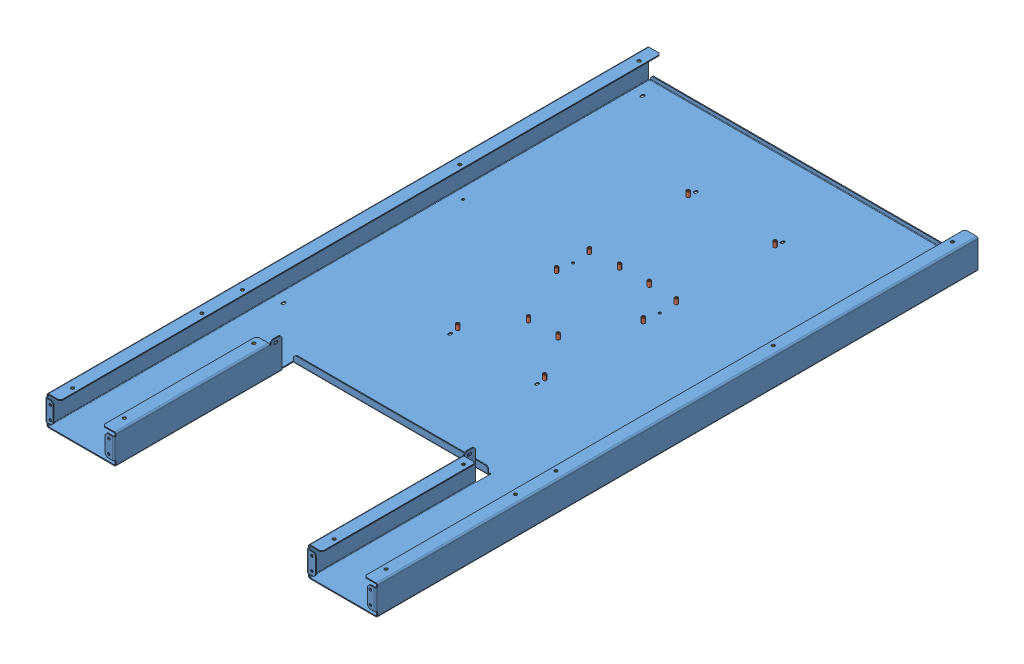
SolidWorks assembly OB_1735311-C_1U-Housing, configuration Default. Lengths in mm.
Overall size (444.51 42.17 812.8).
27 component instances, 3 part files, 11 mates.
Components (placement in the parent):
- OB_1735311-C_1U-Housing-1: OB_1735311-C_1U-Housing [Default] at origin size (444.51 42.17 812.8)
- PEM-STANDOFF_BSO-440-10ZI-5: PEM-STANDOFF_BSO-440-10ZI [93090A420] at (-58.42 3.9688 -154.94) x (0 -1 0) z (1 0 0) size (8.15 5.5 4.76)
- S-440-1ZI_SELF-CLINCHING-NUT-6: S-440-1ZI_SELF-CLINCHING-NUT [95185A120] at (-210.82 36.6268 -241.3) x (1 0 0) z (0 -1 0) size (6.35 6.35 3.2)
- S-440-1ZI_SELF-CLINCHING-NUT-8: S-440-1ZI_SELF-CLINCHING-NUT [95185A120] at (-210.82 36.6268 520.7) x (1 0 0) z (0 -1 0) size (6.35 6.35 3.2)
- S-440-1ZI_SELF-CLINCHING-NUT-9: S-440-1ZI_SELF-CLINCHING-NUT [95185A120] at (-210.82 36.6268 0) x (1 0 0) z (0 -1 0) size (6.35 6.35 3.2)
- S-440-1ZI_SELF-CLINCHING-NUT-10: S-440-1ZI_SELF-CLINCHING-NUT [95185A120] at (-140.97 36.6268 346.71) x (1 0 0) z (0 -1 0) size (6.35 6.35 3.2)
- S-440-1ZI_SELF-CLINCHING-NUT-13: S-440-1ZI_SELF-CLINCHING-NUT [95185A120] at (210.82 36.6268 -241.3) x (-1 0 0) z (0 -1 0) size (6.35 6.35 3.2)
- S-440-1ZI_SELF-CLINCHING-NUT-14: S-440-1ZI_SELF-CLINCHING-NUT [95185A120] at (210.82 36.6268 0) x (-1 0 0) z (0 -1 0) size (6.35 6.35 3.2)
- S-440-1ZI_SELF-CLINCHING-NUT-15: S-440-1ZI_SELF-CLINCHING-NUT [95185A120] at (210.82 36.6268 520.7) x (-1 0 0) z (0 -1 0) size (6.35 6.35 3.2)
- S-440-1ZI_SELF-CLINCHING-NUT-18: S-440-1ZI_SELF-CLINCHING-NUT [95185A120] at (140.97 36.6268 346.71) x (-1 0 0) z (0 -1 0) size (6.35 6.35 3.2)
- PEM-STANDOFF_BSO-440-10ZI-20: PEM-STANDOFF_BSO-440-10ZI [93090A420] at (-58.42 3.9688 -22.098) x (0 -1 0) z (1 0 0) size (8.15 5.5 4.76)
- PEM-STANDOFF_BSO-440-10ZI-21: PEM-STANDOFF_BSO-440-10ZI [93090A420] at (58.42 3.9688 22.098) x (0 -1 0) z (1 0 0) size (8.15 5.5 4.76)
- PEM-STANDOFF_BSO-440-10ZI-22: PEM-STANDOFF_BSO-440-10ZI [93090A420] at (58.42 3.9688 154.94) x (0 -1 0) z (1 0 0) size (8.15 5.5 4.76)
- S-440-1ZI_SELF-CLINCHING-NUT-24: S-440-1ZI_SELF-CLINCHING-NUT [95185A120] at (-140.97 36.6268 520.7) x (1 0 0) z (0 -1 0) size (6.35 6.35 3.2)
- S-440-1ZI_SELF-CLINCHING-NUT-26: S-440-1ZI_SELF-CLINCHING-NUT [95185A120] at (-210.82 36.6268 346.71) x (1 0 0) z (0 -1 0) size (6.35 6.35 3.2)
- S-440-1ZI_SELF-CLINCHING-NUT-27: S-440-1ZI_SELF-CLINCHING-NUT [95185A120] at (-210.82 36.6268 292.1) x (1 0 0) z (0 -1 0) size (6.35 6.35 3.2)
- S-440-1ZI_SELF-CLINCHING-NUT-28: S-440-1ZI_SELF-CLINCHING-NUT [95185A120] at (210.82 36.6268 346.71) x (-1 0 0) z (0 -1 0) size (6.35 6.35 3.2)
- S-440-1ZI_SELF-CLINCHING-NUT-29: S-440-1ZI_SELF-CLINCHING-NUT [95185A120] at (210.82 36.6268 292.1) x (-1 0 0) z (0 -1 0) size (6.35 6.35 3.2)
- S-440-1ZI_SELF-CLINCHING-NUT-30: S-440-1ZI_SELF-CLINCHING-NUT [95185A120] at (140.97 36.6268 520.7) x (-1 0 0) z (0 -1 0) size (6.35 6.35 3.2)
- PEM-STANDOFF_BSO-440-10ZI-1: PEM-STANDOFF_BSO-440-10ZI [93090A420] at (-20 3.9688 -24.2528) x (0 -1 0) z (0 0 1) size (8.15 5.5 4.76)
- PEM-STANDOFF_BSO-440-10ZI-2: PEM-STANDOFF_BSO-440-10ZI [93090A420] at (-20 3.9688 98.2472) x (0 -1 0) z (0 0 1) size (8.15 5.5 4.76)
- PEM-STANDOFF_BSO-440-10ZI-35: PEM-STANDOFF_BSO-440-10ZI [93090A420] at (20 3.9688 98.2472) x (0 -1 0) z (0 0 -1) size (8.15 5.5 4.76)
- PEM-STANDOFF_BSO-440-10ZI-36: PEM-STANDOFF_BSO-440-10ZI [93090A420] at (20 3.9688 -24.2528) x (0 -1 0) z (0 0 -1) size (8.15 5.5 4.76)
- PEM-STANDOFF_BSO-440-10ZI-31: PEM-STANDOFF_BSO-440-10ZI [93090A420] at (-58.42 3.9688 154.94) x (0 -1 0) z (1 0 0) size (8.15 5.5 4.76)
- PEM-STANDOFF_BSO-440-10ZI-32: PEM-STANDOFF_BSO-440-10ZI [93090A420] at (58.42 3.9688 -22.098) x (0 -1 0) z (1 0 0) size (8.15 5.5 4.76)
- PEM-STANDOFF_BSO-440-10ZI-33: PEM-STANDOFF_BSO-440-10ZI [93090A420] at (-58.42 3.9688 22.098) x (0 -1 0) z (1 0 0) size (8.15 5.5 4.76)
- PEM-STANDOFF_BSO-440-10ZI-34: PEM-STANDOFF_BSO-440-10ZI [93090A420] at (58.42 3.9688 -154.94) x (0 -1 0) z (1 0 0) size (8.15 5.5 4.76)
Mates (geometry in assembly coordinates):
- Coincident73: coincident anti-aligned: plane of PEM-STANDOFF_BSO-440-10ZI-5 through (-58.42 0 -154.94) normal (0 -1 0); plane of assembly through (0 0 0) normal (0 1 0)
- Coincident74: coincident aligned: plane of OB_1735311-C_1U-Housing-1 through (0 0 0) normal (0 1 0); plane of assembly through (0 0 0) normal (0 1 0)
- Coincident75: coincident aligned: plane of OB_1735311-C_1U-Housing-1 through (0 0 0) normal (0 0 1); plane of assembly through (0 0 0) normal (0 0 1)
- Coincident76: coincident aligned: plane of OB_1735311-C_1U-Housing-1 through (0 0 0) normal (1 0 0); plane of assembly through (0 0 0) normal (1 0 0)
- Concentric1: concentric aligned: circle of OB_1735311-C_1U-Housing-1; cylinder of PEM-STANDOFF_BSO-440-10ZI-5 through (-58.42 0 -154.94) axis (0 1 0) radius 2.0955
- Coincident78: coincident: plane of S-440-1ZI_SELF-CLINCHING-NUT-6; point of OB_1735311-C_1U-Housing-1
- Coincident79: coincident: plane of S-440-1ZI_SELF-CLINCHING-NUT-6 through (-210.82 36.6268 -241.3) normal (0 0 1); point of OB_1735311-C_1U-Housing-1
- Coincident80: coincident anti-aligned: plane of OB_1735311-C_1U-Housing-1 through (0 38.4048 0) normal (0 -1 0); plane of S-440-1ZI_SELF-CLINCHING-NUT-6 through (-210.82 38.4048 -241.3) normal (0 1 0)
- Parallel1: parallel aligned: plane of S-440-1ZI_SELF-CLINCHING-NUT-6; plane of assembly through (0 0 0) normal (1 0 0)
- Coincident81: coincident anti-aligned: plane of PEM-STANDOFF_BSO-440-10ZI-1 through (-20 0 -24.2528) normal (0 -1 0); plane of assembly through (0 0 0) normal (0 1 0)
- Concentric2: concentric aligned: circle of OB_1735311-C_1U-Housing-1; cylinder of PEM-STANDOFF_BSO-440-10ZI-1 through (-20 0 -24.2528) axis (0 1 0) radius 2.0955
